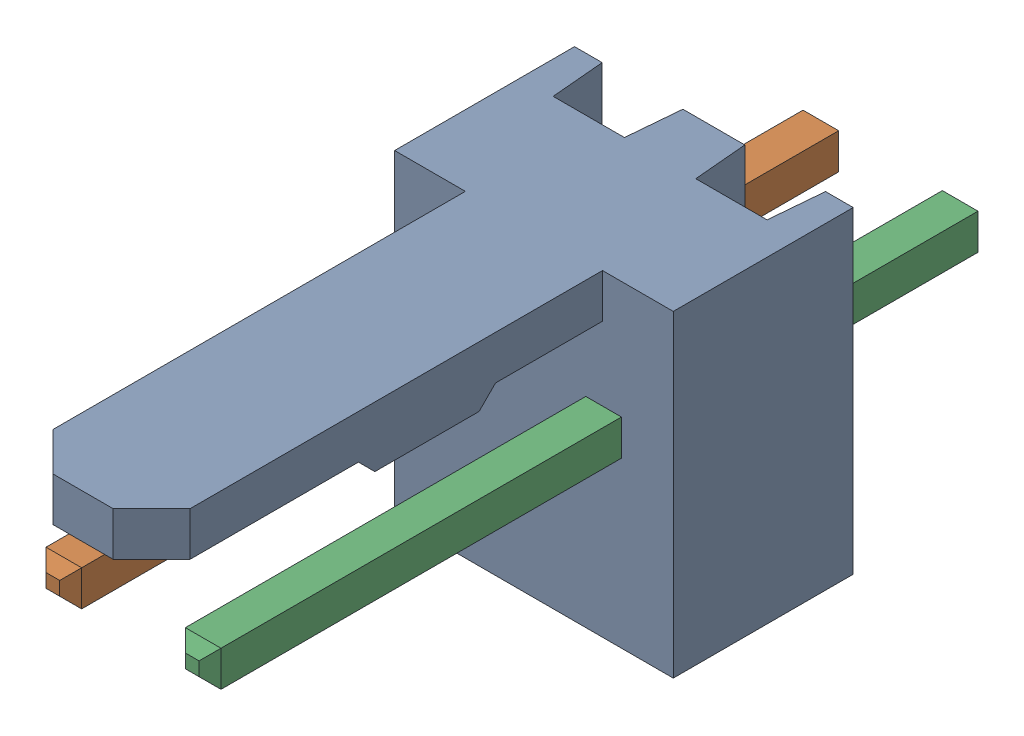
SolidWorks assembly Molex PCB 2 pin v2_5, configuration Predeterminado. Lengths in mm.
Overall size (5.08 5.79 14.92).
3 component instances, 2 part files, 0 mates.
Components (placement in the parent):
- BASE9710016_1-1: BASE9710016_1 [Predeterminado] at (2.54 2.895 -8.22) size (5.08 5.79 11.5)
- PINO9710016_1-1: PINO9710016_1 [Predeterminado] at (1.27 3.325 -0.72) size (0.65 0.65 14.2)
- PINO9710016_1-2: PINO9710016_1 [Predeterminado] at (3.81 3.325 -0.72) size (0.65 0.65 14.2)
